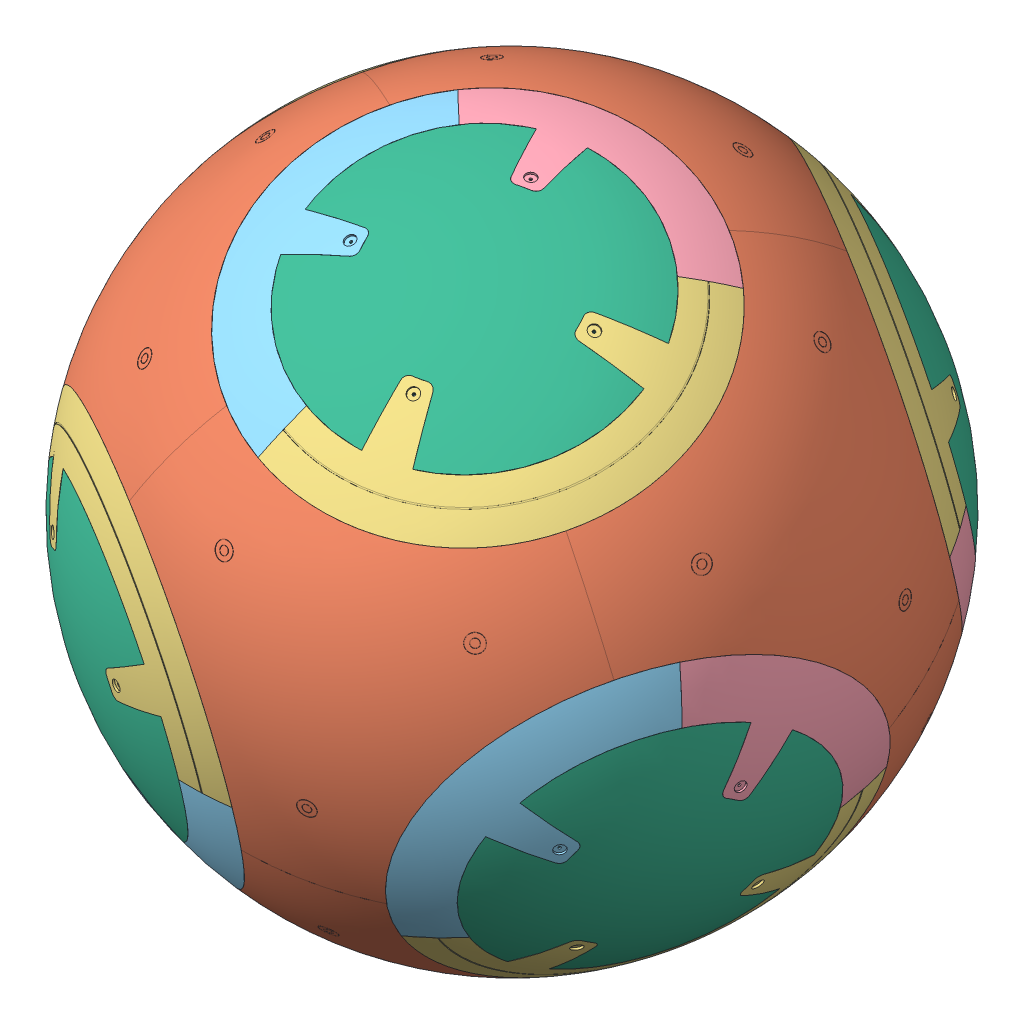
SolidWorks assembly BB-8Test, configuration Default. Lengths in mm.
Overall size (727.46 692.11 742.68).
46 component instances, 7 part files, 48 mates.
Components (placement in the parent):
- BB-8InnerShell-1: BB-8InnerShell [Default] at (789.5056 -133.6259 -382.9718) x (0.265742 -0.402514 0.875993) z (-0.937693 0.103079 0.331823) size (237.5 237.5 237.5)
- BB-8Shell2-2: BB-8Shell2 [Default] at (789.5056 -133.6259 -382.9718) x (0.850957 -0.357508 0.384786) z (-0.475141 -0.211732 0.854055) size (245 215.21 245)
- BB-8InnerShell-2: BB-8InnerShell [Default] at (789.5056 -133.6259 -382.9718) x (0.937693 -0.103079 -0.331823) z (0.265742 -0.402514 0.875993) size (237.5 237.5 237.5)
- BB-8InnerShell-3: BB-8InnerShell [Default] at (789.5056 -133.6259 -382.9718) x (-0.265742 0.402514 -0.875993) z (0.937693 -0.103079 -0.331823) size (237.5 237.5 237.5)
- BB-8InnerShell-4: BB-8InnerShell [Default] at (789.5056 -133.6259 -382.9718) x (-0.937693 0.103079 0.331823) z (-0.265742 0.402514 -0.875993) size (237.5 237.5 237.5)
- BB-8Shell2-3: BB-8Shell2 [Default] at (789.5056 -133.6259 -382.9718) x (-0.850957 0.357508 -0.384786) z (0.475141 0.211732 -0.854055) size (245 215.21 245)
- BB-8Shell2-4: BB-8Shell2 [Default] at (789.5056 -133.6259 -382.9718) x (0.475141 0.211732 -0.854055) z (0.850957 -0.357508 0.384786) size (245 215.21 245)
- BB-8Shell2-5: BB-8Shell2 [Default] at (789.5056 -133.6259 -382.9718) x (-0.475141 -0.211732 0.854055) z (-0.850957 0.357508 -0.384786) size (245 215.21 245)
- BB-8Panel-1: BB-8Panel [Default] at (779.1486 -373.7112 -333.6284) x (-0.177683 0.493461 0.851425) z (0.494268 0.792896 -0.356391) size (286.79 250 286.79)
  - BB-8Shell1-1: BB-8Shell1 [Default] at (74.6203 -96.0057 213.0674) size (215.09 38.2 215.09)
  - BB-8Shell4-1: BB-8Shell4 [Default] at (74.6203 -96.0057 213.0674) x (0 0 -1) z (1 0 0) size (89.69 38.2 195.88)
  - BB-8Shell5-1: BB-8Shell5 [Default] at (74.6203 -96.0057 213.0674) x (-1 0 0) z (0 0 -1) size (89.69 38.2 248.37)
  - BB-8Shell6-1: BB-8Shell6 [Default] at (74.6203 -96.0057 213.0674) size (224.59 250 224.59)
- BB-8InnerShellTop-1: BB-8InnerShellTop [Default] at (789.5056 -133.6259 -382.9718) x (-0.265742 0.402514 -0.875993) z (-0.937693 0.103079 0.331823) size (237.5 205.68 237.5)
- BB-8InnerShellTop-2: BB-8InnerShellTop [Default] at (789.5056 -133.6259 -382.9718) x (0.265742 -0.402514 0.875993) z (0.937693 -0.103079 -0.331823) size (237.5 205.68 237.5)
- BB-8InnerShellTop-3: BB-8InnerShellTop [Default] at (789.5056 -133.6259 -382.9718) x (-0.937693 0.103079 0.331823) z (0.265742 -0.402514 0.875993) size (237.5 205.68 237.5)
- BB-8InnerShellTop-4: BB-8InnerShellTop [Default] at (789.5056 -133.6259 -382.9718) x (0.937693 -0.103079 -0.331823) z (-0.265742 0.402514 -0.875993) size (237.5 205.68 237.5)
- BB-8Shell2-6: BB-8Shell2 [Default] at (789.5056 -133.6259 -382.9718) x (0.22386 0.909592 0.350042) z (0.850957 -0.357508 0.384786) size (245 215.21 245)
- BB-8Shell2-7: BB-8Shell2 [Default] at (789.5056 -133.6259 -382.9718) x (0.22386 0.909592 0.350042) z (-0.475141 -0.211732 0.854055) size (245 215.21 245)
- BB-8Shell2-8: BB-8Shell2 [Default] at (789.5056 -133.6259 -382.9718) x (0.22386 0.909592 0.350042) z (-0.850957 0.357508 -0.384786) size (245 215.21 245)
- BB-8Shell2-9: BB-8Shell2 [Default] at (789.5056 -133.6259 -382.9718) x (-0.850957 0.357508 -0.384786) z (-0.22386 -0.909592 -0.350042) size (245 215.21 245)
- BB-8Panel-2: BB-8Panel [Default] at (754.6638 -299.0226 -205.1715) x (0.937693 -0.103079 -0.331823) z (-0.265742 0.402514 -0.875993) size (286.79 250 286.79) (hidden)
  - BB-8Shell1-1: BB-8Shell1 [Default] at (74.6203 -96.0057 213.0674) size (215.09 38.2 215.09)
  - BB-8Shell4-1: BB-8Shell4 [Default] at (74.6203 -96.0057 213.0674) x (0 0 -1) z (1 0 0) size (89.69 38.2 195.88)
  - BB-8Shell5-1: BB-8Shell5 [Default] at (74.6203 -96.0057 213.0674) x (-1 0 0) z (0 0 -1) size (89.69 38.2 248.37)
  - BB-8Shell6-1: BB-8Shell6 [Default] at (74.6203 -96.0057 213.0674) size (224.59 250 224.59)
- BB-8Panel-3: BB-8Panel [Default] at (872.7342 -3.9178 -192.1008) x (0.443425 -0.895975 0.024568) z (-0.76001 -0.390382 -0.519602) size (286.79 250 286.79)
  - BB-8Shell1-1: BB-8Shell1 [Default] at (74.6203 -96.0057 213.0674) size (215.09 38.2 215.09)
  - BB-8Shell4-1: BB-8Shell4 [Default] at (74.6203 -96.0057 213.0674) x (0 0 -1) z (1 0 0) size (89.69 38.2 195.88)
  - BB-8Shell5-1: BB-8Shell5 [Default] at (74.6203 -96.0057 213.0674) x (-1 0 0) z (0 0 -1) size (89.69 38.2 248.37)
  - BB-8Shell6-1: BB-8Shell6 [Default] at (74.6203 -96.0057 213.0674) size (224.59 250 224.59)
- BB-8Panel-4: BB-8Panel [Default] at (937.5892 -139.7542 -187.481) x (-0.937693 0.103079 0.331823) z (-0.265742 0.402514 -0.875993) size (286.79 250 286.79)
  - BB-8Shell1-1: BB-8Shell1 [Default] at (74.6203 -96.0057 213.0674) size (215.09 38.2 215.09)
  - BB-8Shell4-1: BB-8Shell4 [Default] at (74.6203 -96.0057 213.0674) x (0 0 -1) z (1 0 0) size (89.69 38.2 195.88)
  - BB-8Shell5-1: BB-8Shell5 [Default] at (74.6203 -96.0057 213.0674) x (-1 0 0) z (0 0 -1) size (89.69 38.2 248.37)
  - BB-8Shell6-1: BB-8Shell6 [Default] at (74.6203 -96.0057 213.0674) size (224.59 250 224.59)
- BB-8Panel-5: BB-8Panel [Default] at (706.8329 65.0035 -265.0966) x (-0.494268 -0.792896 0.356391) z (0.177683 -0.493461 -0.851425) size (286.79 250 286.79)
  - BB-8Shell1-1: BB-8Shell1 [Default] at (74.6203 -96.0057 213.0674) size (215.09 38.2 215.09)
  - BB-8Shell4-1: BB-8Shell4 [Default] at (74.6203 -96.0057 213.0674) x (0 0 -1) z (1 0 0) size (89.69 38.2 195.88)
  - BB-8Shell5-1: BB-8Shell5 [Default] at (74.6203 -96.0057 213.0674) x (-1 0 0) z (0 0 -1) size (89.69 38.2 248.37)
  - BB-8Shell6-1: BB-8Shell6 [Default] at (74.6203 -96.0057 213.0674) size (224.59 250 224.59)
- BB-8Panel-6: BB-8Panel [Default] at (797.3546 106.7351 -431.4278) x (-0.76001 -0.390382 -0.519602) z (0.443425 -0.895975 0.024568) size (286.79 250 286.79)
  - BB-8Shell1-1: BB-8Shell1 [Default] at (74.6203 -96.0057 213.0674) size (215.09 38.2 215.09)
  - BB-8Shell4-1: BB-8Shell4 [Default] at (74.6203 -96.0057 213.0674) x (0 0 -1) z (1 0 0) size (89.69 38.2 195.88)
  - BB-8Shell5-1: BB-8Shell5 [Default] at (74.6203 -96.0057 213.0674) x (-1 0 0) z (0 0 -1) size (89.69 38.2 248.37)
  - BB-8Shell6-1: BB-8Shell6 [Default] at (74.6203 -96.0057 213.0674) size (224.59 250 224.59)
Mates (geometry in assembly coordinates):
- Coincident1: coincident anti-aligned: circle of BB-8InnerShell-1; circle of BB-8Shell2-2
- Concentric2: concentric aligned: circle of BB-8InnerShell-1; circle of BB-8Shell2-2
- Coincident3: coincident aligned: circle of BB-8InnerShell-1; circle of BB-8InnerShell-2
- Coincident4: coincident aligned: line of BB-8InnerShell-1 through (842.1126 80.1282 -300.712) axis (0.22386 0.909592 0.350042); line of BB-8InnerShell-2 through (842.1126 80.1282 -300.712) axis (0.22386 0.909592 0.350042)
- Coincident5: coincident aligned: circle of BB-8InnerShell-2; circle of BB-8InnerShell-3
- Coincident6: coincident aligned: line of BB-8InnerShell-2 through (851.9549 -228.2166 -177.1135) axis (0.265742 -0.402514 0.875993); line of BB-8InnerShell-3 through (851.9549 -228.2166 -177.1135) axis (0.265742 -0.402514 0.875993)
- Coincident7: coincident aligned: circle of BB-8InnerShell-3; circle of BB-8InnerShell-4
- Coincident8: coincident aligned: line of BB-8InnerShell-3 through (1009.8634 -157.8494 -460.9503) axis (0.937693 -0.103079 -0.331823); line of BB-8InnerShell-4 through (1009.8634 -157.8494 -460.9503) axis (0.937693 -0.103079 -0.331823)
- Coincident12: coincident anti-aligned: circle of BB-8InnerShell-2; circle of BB-8Shell2-4
- Coincident13: coincident aligned: circle of BB-8Shell2-2; circle of BB-8Shell2-4
- Coincident14: coincident anti-aligned: circle of BB-8InnerShell-3; circle of BB-8Shell2-3
- Coincident15: coincident aligned: circle of BB-8Shell2-3; circle of BB-8Shell2-4
- Coincident16: coincident anti-aligned: circle of BB-8InnerShell-1; circle of BB-8Shell2-5
- Coincident17: coincident aligned: circle of BB-8Shell2-2; circle of BB-8Shell2-5
- Concentric3: concentric: sphere of BB-8Shell2-4; sphere of BB-8Panel-1/BB-8Shell5-1
- Coincident23: coincident aligned: cone of BB-8Shell2-3 through (962.7258 -206.3999 -304.645) axis (-0.850957 0.357508 -0.384786); cone of BB-8Panel-1/BB-8Shell4-1 through (962.7258 -206.3999 -304.645) axis (-0.850957 0.357508 -0.384786)
- Coincident24: coincident anti-aligned: circle of BB-8Shell2-3; circle of BB-8Panel-1/BB-8Shell4-1
- Coincident25: coincident anti-aligned: circle of BB-8InnerShell-3; circle of BB-8InnerShellTop-1
- Tangent1: tangent: circle of BB-8InnerShellTop-1; circle of BB-8InnerShell-4
- Coincident26: coincident anti-aligned: circle of BB-8InnerShell-1; circle of BB-8InnerShellTop-3
- Coincident27: coincident aligned: circle of BB-8InnerShellTop-1; circle of BB-8InnerShellTop-3
- Coincident28: coincident anti-aligned: circle of BB-8InnerShell-2; circle of BB-8InnerShellTop-2
- Coincident29: coincident aligned: circle of BB-8InnerShellTop-2; circle of BB-8InnerShellTop-3
- Coincident30: coincident anti-aligned: circle of BB-8InnerShell-3; circle of BB-8InnerShellTop-4
- Coincident31: coincident aligned: circle of BB-8InnerShellTop-2; circle of BB-8InnerShellTop-4
- Coincident38: coincident anti-aligned: circle of BB-8Shell2-5; circle of BB-8Shell2-8
- Coincident39: coincident aligned: line of BB-8Shell2-5 through (764.9349 -39.5689 -611.6677) axis (-0.098876 0.378499 -0.920305); line of BB-8Shell2-8 through (764.9349 -39.5689 -611.6677) axis (-0.098876 0.378499 -0.920305)
- Coincident40: coincident aligned: circle of BB-8Shell2-3; circle of BB-8Shell2-9
- Coincident41: coincident anti-aligned: line of BB-8Shell2-3 through (1008.831 -141.5302 -502.6961) axis (-0.877302 0.031617 0.478897); line of BB-8Shell2-9 through (1007.515 -141.4827 -501.9777) axis (0.877302 -0.031617 -0.478897)
- Coincident42: coincident anti-aligned: circle of BB-8Shell2-2; circle of BB-8Shell2-7
- Coincident43: coincident aligned: line of BB-8Shell2-2 through (548.5617 -91.0309 -339.567) axis (-0.969593 0.171409 0.174668); line of BB-8Shell2-7 through (548.5617 -91.0309 -339.567) axis (-0.969593 0.171409 0.174668)
- Coincident44: coincident anti-aligned: circle of BB-8Shell2-4; circle of BB-8Shell2-6
- Coincident45: coincident aligned: line of BB-8Shell2-4 through (814.0763 -227.6829 -154.276) axis (0.098876 -0.378499 0.920305); line of BB-8Shell2-6 through (814.0763 -227.6829 -154.276) axis (0.098876 -0.378499 0.920305)
- Coincident46: coincident anti-aligned: plane of BB-8Shell2-8 through (789.5056 -133.6259 -382.9718) normal (-0.538832 0.837355 -0.092179); plane of BB-8Panel-6/BB-8Shell5-1 through (789.5056 -133.6259 -382.9718) normal (0.538832 -0.837355 0.092179)
- Concentric4: concentric: sphere of BB-8Shell2-8; sphere of BB-8Panel-6/BB-8Shell5-1
- Coincident47: coincident aligned: circle of BB-8Shell2-5; circle of BB-8Panel-6/BB-8Shell1-1
- Coincident48: coincident anti-aligned: plane of BB-8Shell2-7 through (789.5056 -133.6259 -382.9718) normal (-0.385862 0.412525 -0.825187); plane of BB-8Panel-2/BB-8Shell1-1 through (789.5056 -133.6259 -382.9718) normal (0.385862 -0.412525 0.825187)
- Concentric5: concentric: sphere of BB-8Shell2-9; sphere of BB-8Panel-2/BB-8Shell1-1
- Coincident49: coincident aligned: circle of BB-8Shell2-9; circle of BB-8Panel-2/BB-8Shell5-1
- Coincident50: coincident aligned: plane of BB-8Shell2-8 through (789.5056 -133.6259 -382.9718) normal (-0.466847 -0.850522 0.242209); plane of BB-8Panel-5/BB-8Shell1-1 through (789.5056 -133.6259 -382.9718) normal (-0.466847 -0.850522 0.242209)
- Concentric6: concentric: sphere of BB-8Shell2-8; sphere of BB-8Panel-5/BB-8Shell1-1
- Coincident51: coincident aligned: circle of BB-8Shell2-8; circle of BB-8Panel-5/BB-8Shell4-1
- Coincident52: coincident anti-aligned: plane of BB-8Shell2-6 through (789.5056 -133.6259 -382.9718) normal (0.811387 0.270094 0.518363); plane of BB-8Panel-3/BB-8Shell5-1 through (789.5056 -133.6259 -382.9718) normal (-0.811387 -0.270094 -0.518363)
- Concentric7: concentric: sphere of BB-8Shell2-4; sphere of BB-8Panel-3/BB-8Shell1-1
- Coincident53: coincident aligned: circle of BB-8Shell2-2; circle of BB-8Panel-3/BB-8Shell4-1
- Coincident54: coincident aligned: plane of BB-8Shell2-5 through (789.5056 -133.6259 -382.9718) normal (-0.964357 0.154736 0.214644); plane of BB-8Panel-4/BB-8Shell1-1 through (789.5056 -133.6259 -382.9718) normal (-0.964357 0.154736 0.214644)
- Concentric8: concentric: sphere of BB-8Shell2-2; sphere of BB-8Panel-4/BB-8Shell5-1
- Coincident55: coincident aligned: circle of BB-8Shell2-2; circle of BB-8Panel-4/BB-8Shell5-1
